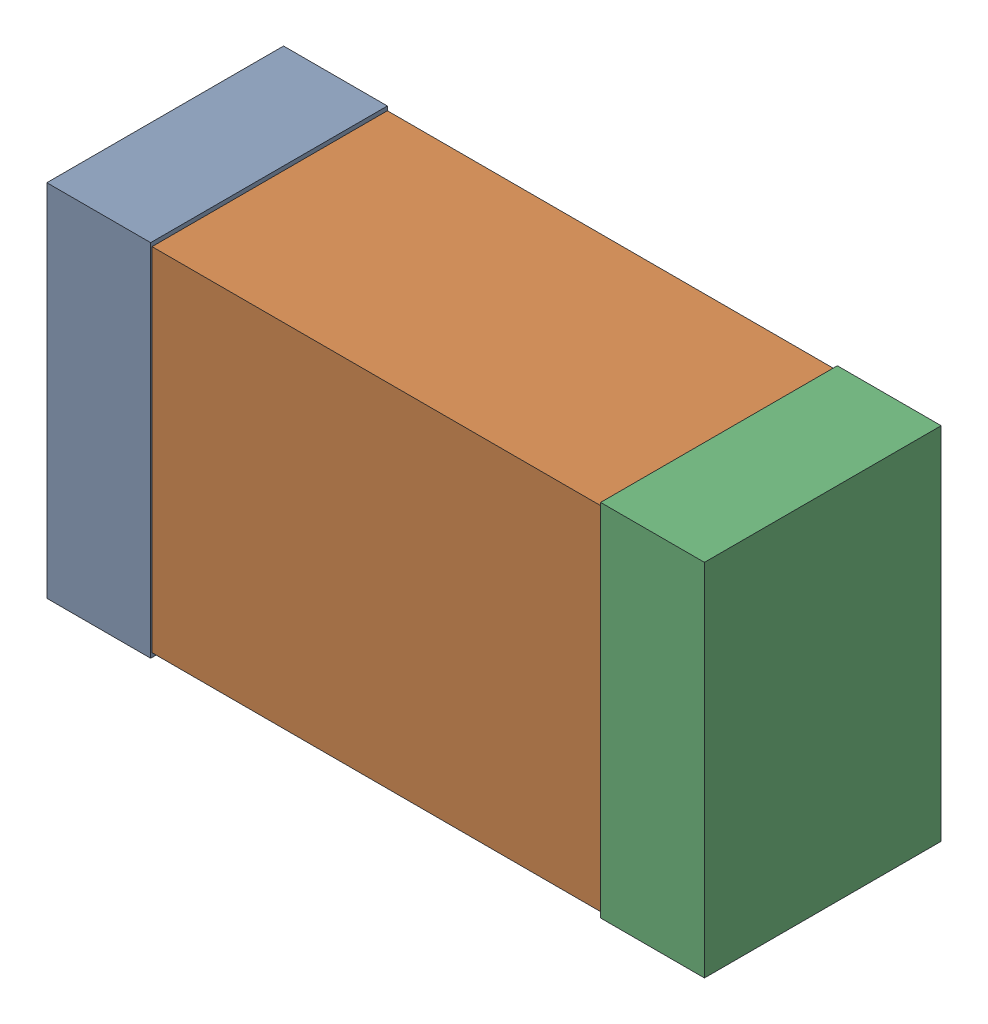
SolidWorks assembly C7Kanaloa_v2.0.0_Motor, configuration Default. Lengths in mm.
Overall size (2.38 1.3 0.85).
6 component instances, 2 part files, 0 mates.
Components (placement in the parent):
- 352877648-1: 352877648 [Default] at (63.0588 117.1448 0) size (0.38 1.3 0.85)
  - Extruded_14-1: Extruded_14 [Default] at origin size (0.38 1.3 0.85)
- 352877904-1: 352877904 [Default] at (64.0588 117.1448 0) size (2.2 1.27 0.85)
  - Extruded_18-1: Extruded_18 [Default] at origin size (2.2 1.27 0.85)
- 352877648-2: 352877648 [Default] at (65.0588 117.1448 0) size (0.38 1.3 0.85)
  - Extruded_14-1: Extruded_14 [Default] at origin size (0.38 1.3 0.85)
